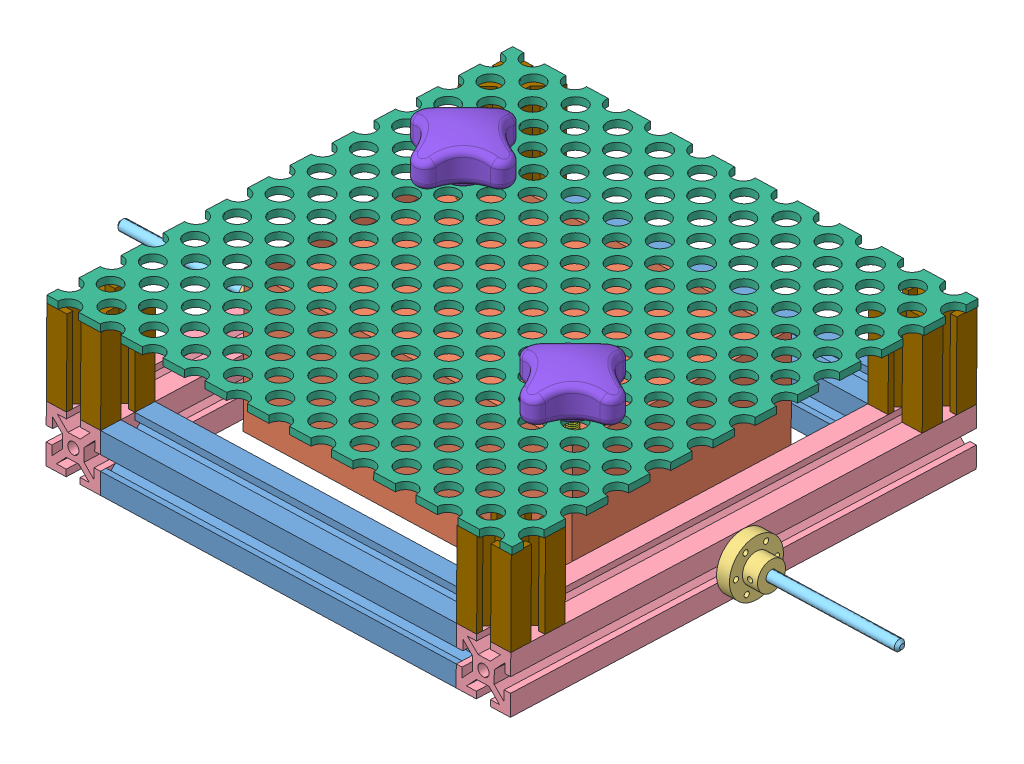
SolidWorks assembly inside, configuration Default. Lengths in mm.
Overall size (362.59 97.6 218.22).
20 component instances, 9 part files, 30 mates.
Components (placement in the parent):
- 1_1_frame_6_8inch-4: 1_1_frame_6_8inch [Default] at (40.1242 118.2314 -229.9268) x (-0.999517 -0.031078 0) z (-0.001152 0.037052 0.999313) size (165.1 25.19 25.19)
- 1_1_frame_6_8inch-5: 1_1_frame_6_8inch [Default] at (40.3439 111.1653 -420.5033) x (-0.999517 -0.031078 0) z (-0.001152 0.037052 0.999313) size (165.1 25.19 25.19)
- Kidney_Mold-1: Kidney_Mold [Default] at (-44.0668 128.9867 -380.6903) x (-0.999517 -0.031078 0) z (0.001152 -0.037052 -0.999313) size (152.4 63.5 101.6)
- Face_Shaft_Collar_revA-1: Face_Shaft_Collar_revA [Default] at (-149.9664 108.7845 -325.2151) x (0.031078 -0.999517 0) z (-0.999517 -0.031078 0) size (25 25 13)
- Face_Shaft_Collar_revA-2: Face_Shaft_Collar_revA [Default] at (65.4143 115.4813 -325.2151) x (0.031078 -0.999517 0) z (0.999517 0.031078 0) size (25 25 13)
- 1_1_frame_7inch-1: 1_1_frame_7inch [Default] at (-137.5007 113.1757 -217.3393) x (0.001152 -0.037052 -0.999313) z (-0.999517 -0.031078 0) size (215.9 25.19 25.19)
- 1_1_frame_7inch-2: 1_1_frame_7inch [Default] at (52.6998 119.0896 -217.3393) x (0.001152 -0.037052 -0.999313) z (-0.999517 -0.031078 0) size (215.9 25.19 25.19)
- rotary_shaft-1: rotary_shaft [Default] at (71.4114 115.6677 -325.2151) x (0 0 -1) z (-0.999517 -0.031078 0) size (4.76 4.76 67.56)
- rotary_shaft-2: rotary_shaft [Default] at (-223.4949 106.4983 -325.2151) x (0 0 -1) z (-0.999517 -0.031078 0) size (4.76 4.76 67.56)
- framing_panel_inside-1: framing_panel_inside [Default] at (-43.643 162.7762 -327.0944) x (0.999517 0.031078 0) z (0.031056 -0.99883 0.03707) size (215.9 215.9 3.17)
- Mold_Clamp_revB-1: Mold_Clamp_revB [Default] at (-22.1467 169.6596 -339.2928) x (0.031056 -0.99883 0.03707) z (-0.001152 0.037052 0.999313) size (70.57 44.45 44.45)
  - 10-32_rod-1: 10-32_rod [95412A897] at (22.5349 40.3264 46.0491) size (64.69 4.89 5.57)
  - threaded_four_arm_knob-1: threaded_four_arm_knob [2454K23] at (-2.8651 40.3264 46.0491) x (0 0 1) z (-1 0 0) size (44.45 44.45 19.36)
- Mold_Clamp_revB-3: Mold_Clamp_revB [Default] at (-62.6703 165.7857 -409.7216) x (0.031056 -0.99883 0.03707) z (-0.999517 -0.031078 0) size (70.57 44.45 44.45)
  - 10-32_rod-1: 10-32_rod [95412A897] at (22.5349 40.3264 46.0491) size (64.69 4.89 5.57)
  - threaded_four_arm_knob-1: threaded_four_arm_knob [2454K23] at (-2.8651 40.3264 46.0491) x (0 0 1) z (-1 0 0) size (44.45 44.45 19.36)
- 1_1_frame_1_inch-1: 1_1_frame_1_inch [Default] at (-137.6577 118.2243 -420.9703) x (-0.031056 0.99883 -0.03707) z (-0.001152 0.037052 0.999313) size (38.1 25.19 25.19)
- 1_1_frame_1_inch-2: 1_1_frame_1_inch [Default] at (-137.8774 125.2905 -230.3938) x (-0.031056 0.99883 -0.03707) z (-0.001152 0.037052 0.999313) size (38.1 25.19 25.19)
- 1_1_frame_1_inch-3: 1_1_frame_1_inch [Default] at (52.3231 131.2043 -230.3938) x (-0.031056 0.99883 -0.03707) z (-0.001152 0.037052 0.999313) size (38.1 25.19 25.19)
- 1_1_frame_1_inch-4: 1_1_frame_1_inch [Default] at (52.5428 124.1382 -420.9703) x (-0.031056 0.99883 -0.03707) z (-0.001152 0.037052 0.999313) size (38.1 25.19 25.19)
Mates (geometry in assembly coordinates):
- Coincident29: coincident aligned: line of 1_1_frame_6_8inch-4 through (39.7293 130.9329 -227.156) axis (-0.001152 0.037052 0.999313); line of 1_1_frame_7inch-2 through (39.9672 123.28 -433.5578) axis (-0.001152 0.037052 0.999313)
- Coincident30: coincident aligned: line of 1_1_frame_6_8inch-4 through (-125.291 125.802 -227.156) axis (-0.001152 0.037052 0.999313); line of 1_1_frame_7inch-1 through (-125.053 118.1491 -433.5578) axis (-0.001152 0.037052 0.999313)
- Coincident32: coincident anti-aligned: line of 1_1_frame_6_8inch-4 through (-124.5194 100.9857 -216.8723) axis (0.999517 0.031078 0); line of 1_1_frame_7inch-2 through (49.8525 106.4075 -216.8723) axis (-0.999517 -0.031078 0)
- Coincident35: coincident aligned: line of 1_1_frame_6_8inch-4 through (-124.5194 100.9857 -216.8723) axis (0.999517 0.031078 0); line of 1_1_frame_7inch-1 through (-133.8711 100.695 -216.8723) axis (0.999517 0.031078 0)
- Coincident36: coincident aligned: line of 1_1_frame_6_8inch-5 through (-124.2707 92.9861 -432.6239) axis (0.999517 0.031078 0); line of 1_1_frame_7inch-1 through (-133.6223 92.6954 -432.6239) axis (0.999517 0.031078 0)
- Coincident37: coincident anti-aligned: line of 1_1_frame_6_8inch-5 through (-124.2707 92.9861 -432.6239) axis (0.999517 0.031078 0); line of 1_1_frame_7inch-2 through (50.1013 98.4078 -432.6239) axis (-0.999517 -0.031078 0)
- Coincident38: coincident anti-aligned: line of 1_1_frame_6_8inch-5 through (40.7388 98.4637 -423.2742) axis (0.001152 -0.037052 -0.999313); line of 1_1_frame_7inch-2 through (40.7496 98.1171 -432.6239) axis (-0.001152 0.037052 0.999313)
- Coincident39: coincident anti-aligned: plane of Face_Shaft_Collar_revA-1 through (-149.9664 108.7845 -325.2151) normal (0.999517 0.031078 0); plane of 1_1_frame_7inch-1 through (-149.8421 104.7847 -433.0909) normal (-0.999517 -0.031078 0)
- Concentric7: concentric anti-aligned: circle of Face_Shaft_Collar_revA-1; circle of 1_1_frame_7inch-1
- Coincident40: coincident anti-aligned: plane of Face_Shaft_Collar_revA-2 through (65.4143 115.4813 -325.2151) normal (-0.999517 -0.031078 0); plane of 1_1_frame_7inch-2 through (65.5386 111.4815 -433.0909) normal (0.999517 0.031078 0)
- Concentric8: concentric anti-aligned: circle of Face_Shaft_Collar_revA-2; circle of 1_1_frame_7inch-2
- Coincident42: coincident anti-aligned: plane of Face_Shaft_Collar_revA-2 through (71.4114 115.6677 -325.2151) normal (0.999517 0.031078 0); circle of rotary_shaft-1
- Concentric14: concentric anti-aligned: circle of Face_Shaft_Collar_revA-2; cylinder of rotary_shaft-1 through (138.9427 117.7675 -325.2151) axis (-0.999517 -0.031078 0) radius 2.3813
- Coincident43: coincident anti-aligned: plane of Face_Shaft_Collar_revA-1 through (-155.9635 108.598 -325.2151) normal (-0.999517 -0.031078 0); plane of rotary_shaft-2 through (-155.9635 108.598 -325.2151) normal (0.999517 0.031078 0)
- Concentric15: concentric aligned: circle of Face_Shaft_Collar_revA-1; cylinder of rotary_shaft-2 through (-155.9635 108.598 -325.2151) axis (-0.999517 -0.031078 0) radius 2.3813
- Coincident45: coincident anti-aligned: line of 1_1_frame_6_8inch-5 through (-125.053 118.1491 -433.5578) axis (0.999517 0.031078 0); line of 1_1_frame_1_inch-1 through (-140.8816 117.6569 -433.5578) axis (-0.999517 -0.031078 0)
- Coincident46: coincident aligned: line of 1_1_frame_7inch-1 through (-150.2333 117.3661 -433.5578) axis (-0.001152 0.037052 0.999313); line of 1_1_frame_1_inch-1 through (-150.2515 117.9529 -417.7325) axis (-0.001152 0.037052 0.999313)
- Coincident47: coincident anti-aligned: line of 1_1_frame_7inch-1 through (-150.2333 117.3661 -433.5578) axis (-0.001152 0.037052 0.999313); line of 1_1_frame_1_inch-2 through (-150.4638 124.779 -233.6315) axis (0.001152 -0.037052 -0.999313)
- Coincident48: coincident aligned: line of 1_1_frame_7inch-1 through (-141.1303 125.6565 -217.8062) axis (-0.999517 -0.031078 0); line of 1_1_frame_1_inch-2 through (-141.1303 125.6565 -217.8062) axis (-0.999517 -0.031078 0)
- Coincident49: coincident anti-aligned: line of 1_1_frame_6_8inch-4 through (-125.3018 126.1487 -217.8062) axis (0.999517 0.031078 0); line of 1_1_frame_1_inch-3 through (49.0701 131.5704 -217.8062) axis (-0.999517 -0.031078 0)
- Coincident50: coincident aligned: line of 1_1_frame_7inch-2 through (65.1474 124.0629 -433.5578) axis (-0.001152 0.037052 0.999313); line of 1_1_frame_1_inch-3 through (64.9095 131.7158 -227.156) axis (-0.001152 0.037052 0.999313)
- Coincident51: coincident aligned: line of 1_1_frame_7inch-2 through (65.1474 124.0629 -433.5578) axis (-0.001152 0.037052 0.999313); line of 1_1_frame_1_inch-4 through (65.1292 124.6497 -417.7325) axis (-0.001152 0.037052 0.999313)
- Coincident52: coincident aligned: line of 1_1_frame_6_8inch-5 through (-125.053 118.1491 -433.5578) axis (0.999517 0.031078 0); line of 1_1_frame_1_inch-4 through (55.7957 123.7721 -433.5578) axis (0.999517 0.031078 0)
- Coincident56: coincident anti-aligned: plane of Kidney_Mold-1 through (30.9933 166.8322 -280.3372) normal (-0.031056 0.99883 -0.03707); plane of framing_panel_inside-1 through (-43.643 162.7762 -327.0944) normal (0.031056 -0.99883 0.03707)
- Concentric16: concentric anti-aligned: circle of Kidney_Mold-1; circle of Mold_Clamp_revB-1/10-32_rod-1
- Coincident57: coincident anti-aligned: plane of framing_panel_inside-1 through (-43.7416 165.9475 -327.2121) normal (-0.031056 0.99883 -0.03707); plane of Mold_Clamp_revB-1/threaded_four_arm_knob-1 through (26.8473 169.4066 -293.1461) normal (0.031056 -0.99883 0.03707)
- Concentric17: concentric anti-aligned: circle of Kidney_Mold-1; circle of Mold_Clamp_revB-3/10-32_rod-1
- Coincident58: coincident anti-aligned: plane of framing_panel_inside-1 through (-43.7416 165.9475 -327.2121) normal (-0.031056 0.99883 -0.03707); plane of Mold_Clamp_revB-3/threaded_four_arm_knob-1 through (-108.6454 162.6879 -360.6637) normal (0.031056 -0.99883 0.03707)
- Coincident59: coincident aligned: line of framing_panel_inside-1 through (-146.4303 163.5839 -219.2186) axis (-0.999517 -0.031078 0); line of 1_1_frame_1_inch-2 through (-142.3136 163.7119 -219.2186) axis (-0.999517 -0.031078 0)
- Coincident61: coincident aligned: line of framing_panel_inside-1 through (-151.6482 162.8726 -234.0141) axis (0.001152 -0.037052 -0.999313); line of 1_1_frame_1_inch-2 through (-151.647 162.8344 -235.0439) axis (0.001152 -0.037052 -0.999313)
